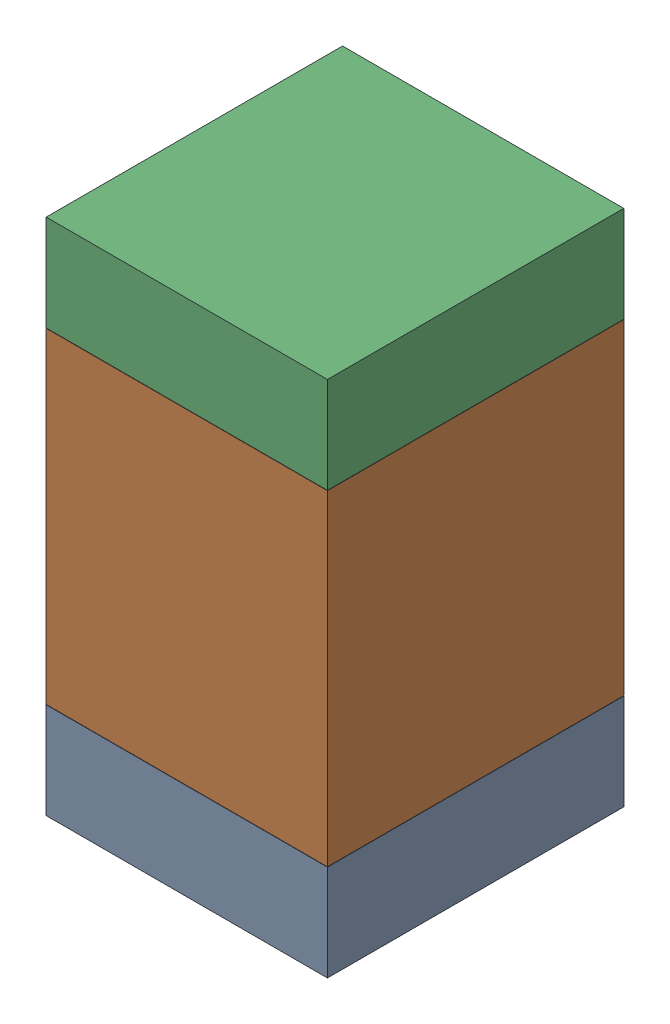
SolidWorks assembly R28, configuration Default. Lengths in mm.
Overall size (0.95 1.75 1).
6 component instances, 2 part files, 0 mates.
Components (placement in the parent):
- 6575495072-1: 6575495072 [Default] at (0.889 42.5945 0) size (0.95 0.32 1)
  - Extruded_6-1: Extruded_6 [Default] at origin size (0.95 0.32 1)
- 6575494912-1: 6575494912 [Default] at (0.889 43.307 0) size (0.95 1.1 1)
  - Extruded_7-1: Extruded_7 [Default] at origin size (0.95 1.1 1)
- 6575495072-2: 6575495072 [Default] at (0.889 44.0195 0) size (0.95 0.32 1)
  - Extruded_6-1: Extruded_6 [Default] at origin size (0.95 0.32 1)
